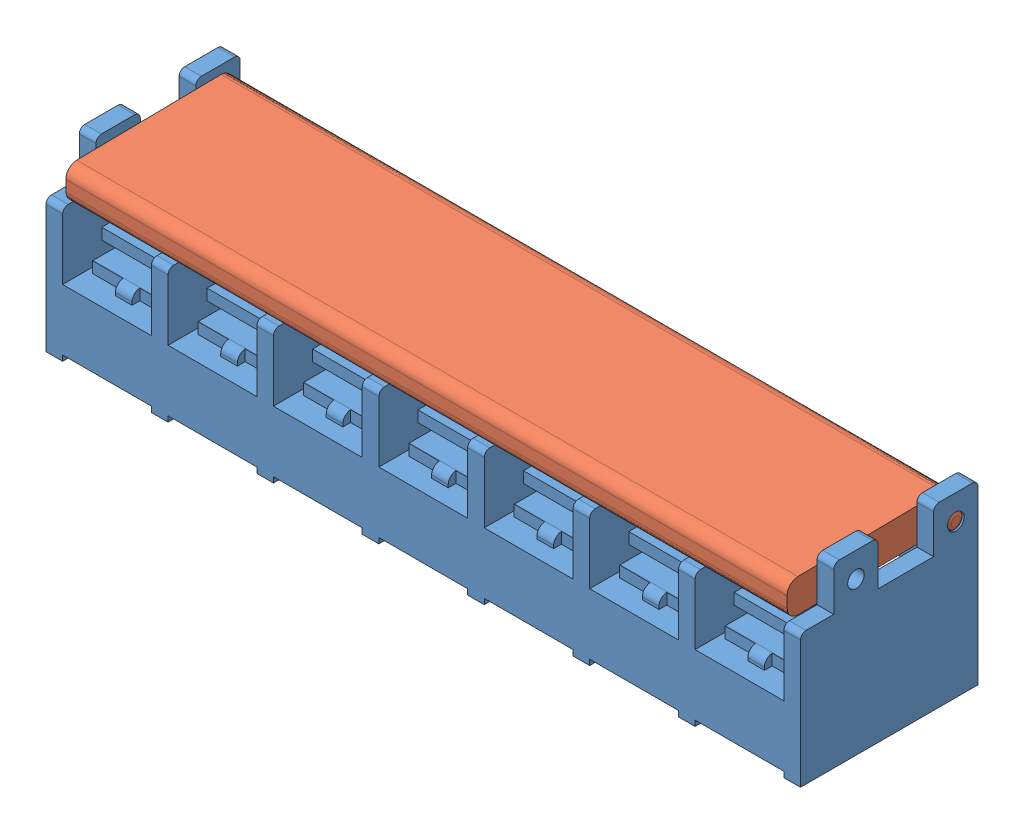
SolidWorks assembly HB-9500, configuration 7. Lengths in mm.
Overall size (68 20.7 16).
2 component instances, 2 part files, 2 mates.
Components (placement in the parent):
- Base^HB-9500-1: Base^HB-9500 [7pin] at origin size (68 20.7 16) (virtual)
- Lid^HB-9500-1: Lid^HB-9500 [7] at (34 12.1621 -7.8151) x (-1 0 0) z (0 0.014184 -0.999899) size (68 3 15) (virtual)
Mates (geometry in assembly coordinates):
- Concentric1: concentric anti-aligned: cylinder of Base^HB-9500-1 through (1.5 13.75 -14) axis (-1 0 0) radius 0.75; cylinder of Lid^HB-9500-1 through (0 13.75 -14) axis (1 0 0) radius 0.8
- Coincident1: coincident anti-aligned: plane of Base^HB-9500-1 through (1.5 0 0) normal (1 0 0); plane of Lid^HB-9500-1 through (1.5 15.1618 -7.7726) normal (-1 0 0)
